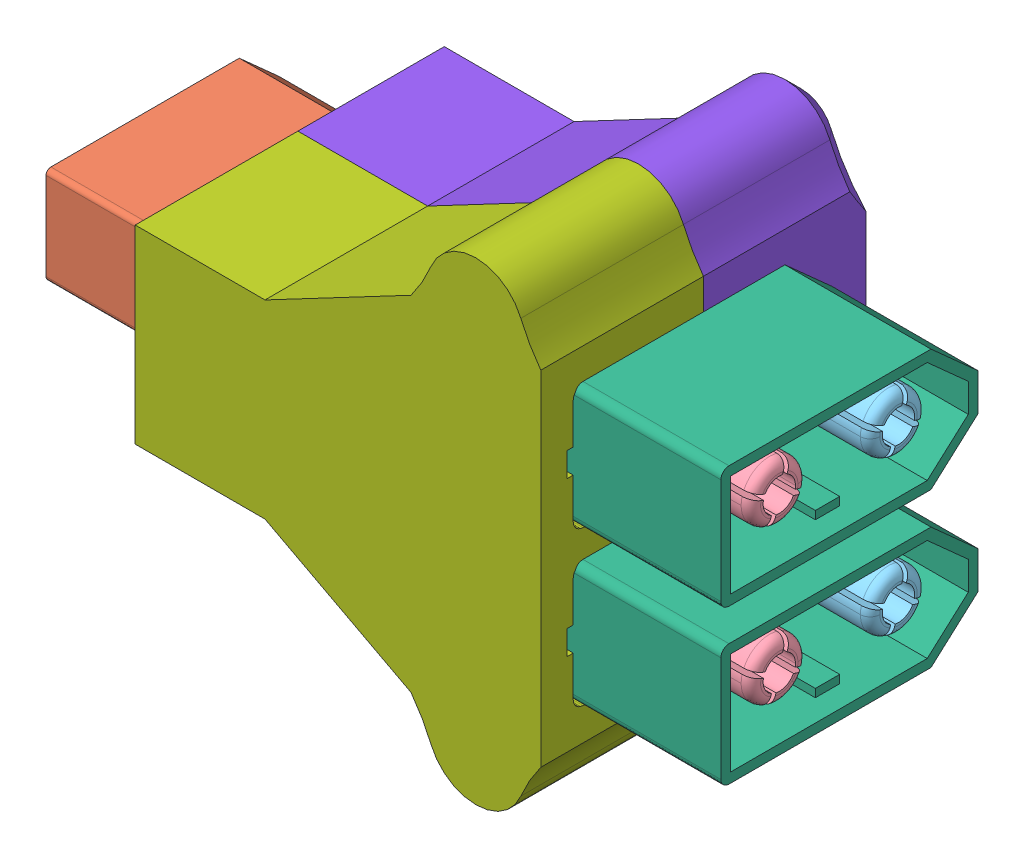
SolidWorks assembly Adapter, configuration Default. Lengths in mm.
Overall size (42.7 29.2 20.05).
17 component instances, 8 part files, 22 mates.
Components (placement in the parent):
- XT60MaleConnector-3: XT60MaleConnector [Default] at (-8 0 0) size (20.2 7.5 16.55)
  - XT60MaleConnector.STEP-1: XT60MaleConnector.STEP [Default] at origin size (20.2 7.5 16.55)
    - XT60MaleConnector1.STEP-1: XT60MaleConnector1.STEP [Default] at origin size (19.85 4.2 4.2)
    - XT60MaleConnector2.STEP-1: XT60MaleConnector2.STEP [Default] at origin size (15.7 7.5 16.55)
    - XT60MaleConnector3.STEP-1: XT60MaleConnector3.STEP [Default] at origin size (19.85 4.2 4.2)
- XT60FemaleConnector-4: XT60FemaleConnector [Default] at (19 -4.75 0) x (-1 0 0) z (0 0 1) size (20.5 7.5 16.55)
  - XT60FemaleConnector.STEP-1: XT60FemaleConnector.STEP [Default] at origin size (20.5 7.5 16.55)
    - XT60FemaleConnector1.STEP-1: XT60FemaleConnector1.STEP [Default] at origin size (19.86 4.2 4.2)
    - XT60FemaleConnector2.STEP-1: XT60FemaleConnector2.STEP [Default] at origin size (19.86 4.2 4.2)
    - XT60FemaleConnector3.STEP-1: XT60FemaleConnector3.STEP [Default] at origin size (16 7.5 16.55)
- XT60FemaleConnector-5: XT60FemaleConnector [Default] at (19 4.75 0) x (-1 0 0) z (0 0 1) size (20.5 7.5 16.55)
  - XT60FemaleConnector.STEP-1: XT60FemaleConnector.STEP [Default] at origin size (20.5 7.5 16.55)
    - XT60FemaleConnector1.STEP-1: XT60FemaleConnector1.STEP [Default] at origin size (19.86 4.2 4.2)
    - XT60FemaleConnector2.STEP-1: XT60FemaleConnector2.STEP [Default] at origin size (19.86 4.2 4.2)
    - XT60FemaleConnector3.STEP-1: XT60FemaleConnector3.STEP [Default] at origin size (16 7.5 16.55)
- Adapter Bottom-1: Adapter Bottom [Default] at (11 4.55 0) x (0 0 -1) z (-1 0 0) size (10.02 29.2 25)
- Adapter Top-1: Adapter Top [Default] at (11 4.55 0) x (0 0 -1) z (-1 0 0) size (10.03 29.2 25)
Mates (geometry in assembly coordinates):
- Coincident1: coincident: plane of assembly through (8 -3.75 6.475) normal (0 0 1); plane of ? through (8 5.75 6.475) normal (0 0 1)
- Coincident2: coincident: plane of ? through (8 5.75 6.475) normal (0 0 1); plane of ? through (-16.4368 1.384 6.475) normal (0 0 1)
- Coincident3: coincident: plane of assembly through (8 0 0) normal (1 0 0); plane of ? through (8 9.5 0) normal (1 0 0)
- Distance1: distance = 2 mm: plane of assembly through (8 3.75 6.475) normal (0 1 0); plane of ? through (8 5.75 -6.475) normal (0 -1 0)
- Coincident6: coincident: plane of ? through (0 0 0) normal (1 0 0); plane of assembly through (0 0 0) normal (1 0 0)
- Coincident7: coincident: point of ?
- Coincident8: coincident: plane of ? through (0 -3.75 6.475) normal (0 0 1); plane of ? through (11 -1 6.475) normal (0 0 1)
- Coincident9: coincident: plane of ? through (0 -3.75 6.475) normal (0 0 1); plane of ? through (11 8.5 6.475) normal (0 0 1)
- Distance3: distance = 2 mm: plane of ? through (6.5 4.75 2.225) normal (-1 0 0); plane of ? through (4.5 0 2.225) normal (1 0 0)
- Distance4: distance = 2 mm: plane of ? through (6.5 -4.75 2.225) normal (-1 0 0); plane of ? through (4.5 0 2.225) normal (1 0 0)
- Distance6: distance = 2 mm: plane of ? through (11 -1 -6.475) normal (0 1 0); plane of ? through (11 1 6.475) normal (0 -1 0)
- Distance7: distance = 1 mm: plane of ? through (11 -1 -6.475) normal (0 1 0); plane of assembly through (0 0 0) normal (0 1 0)
- InPlace1: in place: plane of ? through (11 4.75 0) normal (-1 0 0); plane of ? through (11 0 0) normal (-1 0 0); moOrthogonalPlaneRef_w of ? through (11 4.75 0) normal (-1 0 0); plane of ? through (11 0 0) normal (0 1 0); plane of ? through (11 4.75 0) normal (-1 0 0); plane of ? through (11 0 0) normal (0 0 1); plane of ? through (11 4.75 0) normal (-1 0 0); unknown of ?
- Coincident15: coincident: plane of assembly; plane of assembly; plane of XT60FemaleConnector-5/XT60FemaleConnector.STEP-1/XT60FemaleConnector3.STEP-1; plane of ?
- Coincident16: coincident: plane of ? through (11 4.75 0) normal (0 -1 0); plane of ? through (11 4.75 0) normal (0 -1 0)
- Coincident17: coincident: plane of ? through (11 4.75 0) normal (0 0 1); plane of ? through (11 4.75 0) normal (0 0 -1)
- Coincident18: coincident: plane of ? through (11 4.55 -1.45) normal (0 0 -1); plane of ? through (11 4.55 -1.45) normal (0 0 1)
- Coincident19: coincident: plane of ? through (-7 5.65 0) normal (0 1 0); plane of ? through (-7 5.65 0) normal (0 1 0)
- Coincident20: coincident: plane of ? through (-7 4.55 0) normal (-1 0 0); plane of ? through (-7 4.55 0) normal (-1 0 0)
- Distance8: distance = 7 mm: plane of ? through (-7 4.55 0) normal (-1 0 0); plane of ? through (0 0 0) normal (1 0 0)
- Distance9: distance = 0.1 mm: plane of ? through (-7 3.65 0) normal (0 -1 0); plane of ? through (0 3.75 6.475) normal (0 1 0)
- Distance10: distance = 0.1 mm: plane of ? through (-7 4.55 6.575) normal (0 0 -1); plane of ? through (0 -3.75 6.475) normal (0 0 1)
